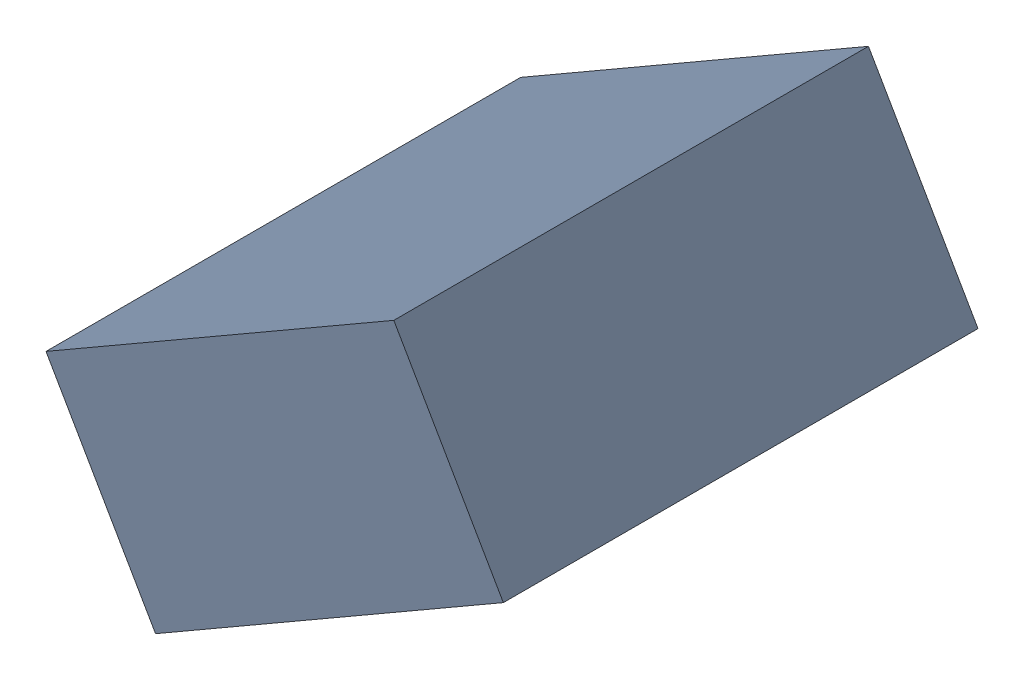
SolidWorks assembly C22_TDA5, configuration Standard. Lengths in mm.
Overall size (1.25 1.07 1.3).
2 component instances, 1 part files, 0 mates.
Components (placement in the parent):
- 885542920-1: 885542920 [Standard] at (-42.5634 -33.0538 0) size (1.25 1.07 1.3)
  - Extruded_24-1: Extruded_24 [Standard] at origin size (1.25 1.07 1.3)
